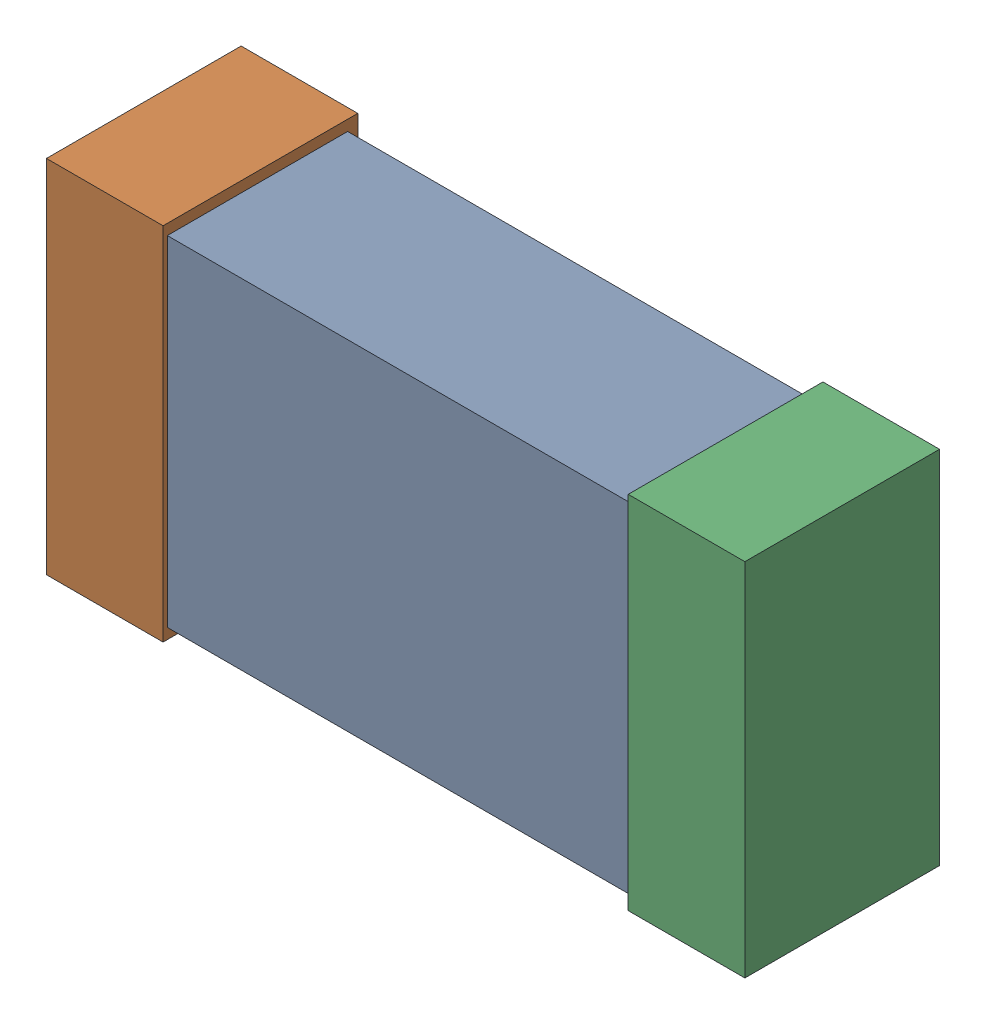
SolidWorks assembly R1, configuration Default. Lengths in mm.
Overall size (1.65 0.85 0.46).
6 component instances, 2 part files, 0 mates.
Components (placement in the parent):
- 432120720_13-1: 432120720_13 [Default] at (34.8459 19.8613 0.025) size (1.5 0.8 0.42)
  - Extruded (12)-1: Extruded (12) [Default] at origin size (1.5 0.8 0.42)
- 432120464_28-1: 432120464_28 [Default] at (34.1601 19.8613 0.001) size (0.28 0.85 0.46)
  - Extruded (11)-1: Extruded (11) [Default] at origin size (0.28 0.85 0.46)
- 432120464_29-1: 432120464_29 [Default] at (35.5316 19.8613 0.001) size (0.28 0.85 0.46)
  - Extruded (11)-1: Extruded (11) [Default] at origin size (0.28 0.85 0.46)
